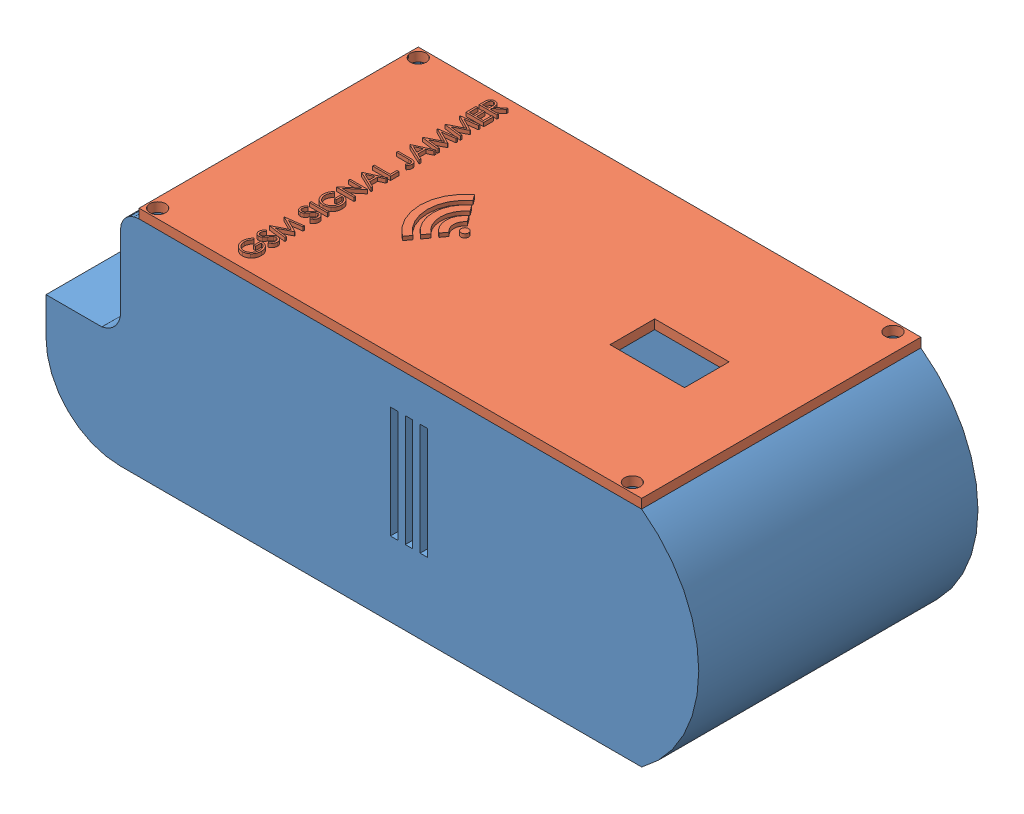
SolidWorks assembly Assem1, configuration Default. Lengths in mm.
Overall size (175.34 63.5 75).
2 component instances, 2 part files, 2 mates.
Components (placement in the parent):
- Base-1: Base [Default] at (-8.454 82.4446 179.7447) size (175.34 60.01 75)
- Top Cover-1: Top Cover [Default] at (-3.454 107.4446 217.2447) size (135 3.5 75)
Mates (geometry in assembly coordinates):
- Coincident3: coincident aligned: line of Base-1 through (-3.454 107.4446 217.2447) axis (1 0 0); line of Top Cover-1 through (-3.454 107.4446 217.2447) axis (1 0 0)
- Coincident4: coincident anti-aligned: line of Base-1 through (-3.454 107.4446 212.2447) axis (0 0 -1); line of Top Cover-1 through (-3.454 107.4446 142.2447) axis (0 0 1)
